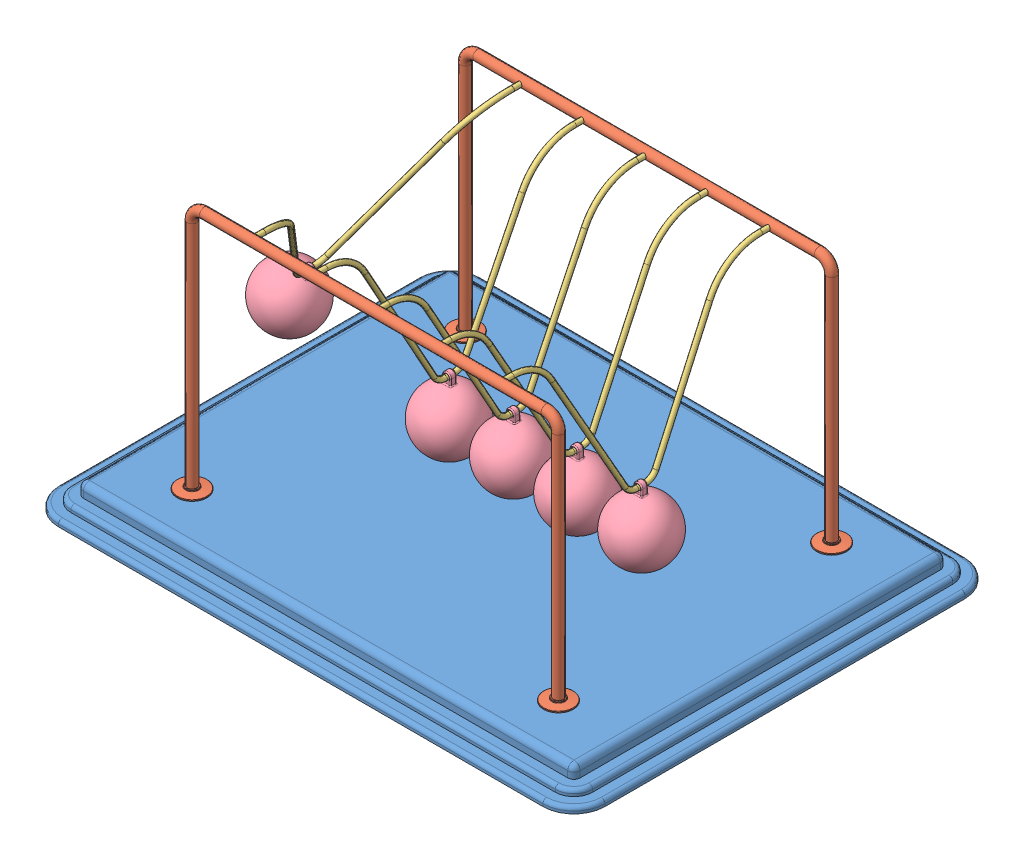
SolidWorks assembly Newtons Cradle NewtonsCradle 0247, configuration Default. Lengths in mm.
Overall size (440 222 340).
13 component instances, 4 part files, 34 mates.
Components (placement in the parent):
- Base 200,162074554295-1: Base 200,162074554295 [Default] at (-16.2968 -4.1587 11.425) size (440 20 340)
- frame NewtonsCradle 0247-1: frame NewtonsCradle 0247 [Default] at (-16.2968 144.4547 -98.575) size (319 202 24)
- frame NewtonsCradle 0247-2: frame NewtonsCradle 0247 [Default] at (-16.2968 144.4547 121.425) x (-1 0 0) z (0 0 -1) size (319 202 24)
- Hanging thing NewtonsCradle 0247-1: Hanging thing NewtonsCradle 0247 [Default] at (-157.6326 134.1825 11.425) x (0 0 1) z (-0.859985 0.510319 0) size (220 129 4)
- Hanging thing NewtonsCradle 0247-2: Hanging thing NewtonsCradle 0247 [Default] at (-66.576 122.8418 11.425) x (0 0 1) z (-0.999994 0.003446 0) size (220 129 4)
- Hanging thing NewtonsCradle 0247-3: Hanging thing NewtonsCradle 0247 [Default] at (-15.6923 122.8436 11.425) x (0 0 1) z (-0.999972 -0.007464 0) size (220 129 4)
- Hanging thing NewtonsCradle 0247-4: Hanging thing NewtonsCradle 0247 [Default] at (35.2213 122.8555 11.425) x (0 0 1) z (-0.999824 -0.018742 0) size (220 129 4)
- Hanging thing NewtonsCradle 0247-5: Hanging thing NewtonsCradle 0247 [Default] at (86.0287 122.8747 11.425) x (0 0 1) z (-0.999588 -0.028711 0) size (220 129 4)
- Sphere NewtonsCradle 0247-1: Sphere NewtonsCradle 0247 [Default] at (-195.3962 70.5436 11.425) x (0.859985 -0.510319 0) z (0 0 1) size (50 58.5 50)
- Sphere NewtonsCradle 0247-2: Sphere NewtonsCradle 0247 [Default] at (88.1533 48.9052 11.425) x (0.999588 0.028711 0) z (0 0 1) size (50 58.5 50)
- Sphere NewtonsCradle 0247-3: Sphere NewtonsCradle 0247 [Default] at (-15.14 48.8456 11.425) x (0.999972 0.007464 0) z (0 0 1) size (50 58.5 50)
- Sphere NewtonsCradle 0247-4: Sphere NewtonsCradle 0247 [Default] at (36.6081 48.8685 11.425) x (0.999824 0.018742 0) z (0 0 1) size (50 58.5 50)
- Sphere NewtonsCradle 0247-5: Sphere NewtonsCradle 0247 [Default] at (-66.831 48.8422 11.425) x (0.999994 -0.003446 0) z (0 0 1) size (50 58.5 50)
Mates (geometry in assembly coordinates):
- Coincident1: coincident anti-aligned: plane of Base-1 through (-211.2968 5.8413 156.425) normal (0 1 0); plane of frame-2 through (-175.7968 5.8413 121.425) normal (0 -1 0)
- Coincident2: coincident anti-aligned: plane of Base-1 through (-211.2968 5.8413 156.425) normal (0 1 0); plane of frame-1 through (143.2032 5.8413 -98.575) normal (0 -1 0)
- Concentric1: concentric anti-aligned: cylinder of frame-1 through (-116.2968 203.8413 -94.575) axis (0 0 -1) radius 2; cylinder of frame-2 through (-116.2968 203.8413 117.425) axis (0 0 1) radius 2
- Concentric2: concentric anti-aligned: cylinder of frame-1 through (83.7032 203.8413 -94.575) axis (0 0 -1) radius 2; cylinder of frame-2 through (83.7032 203.8413 117.425) axis (0 0 1) radius 2
- Distance1: distance = 60 mm: plane of frame-1 through (-16.2968 144.4547 -98.575) normal (0 0 1); line of Base-1 through (-211.2968 -12.1587 -158.575) axis (1 0 0)
- Distance2: distance = 60 mm: line of Base-1 through (178.7032 -12.1587 181.425) axis (-1 0 0); plane of frame-2 through (-16.2968 144.4547 121.425) normal (0 0 -1)
- Distance3: distance = 220 mm: plane of frame-2 through (-16.2968 144.4547 121.425) normal (-1 0 0); line of Base-1 through (-236.2968 -12.1587 156.425) axis (0 0 -1)
- Concentric3: concentric anti-aligned: cylinder of frame-1 through (-116.2968 203.8413 -94.575) axis (0 0 -1) radius 2; cylinder of Hanging thing-1 through (-116.2968 203.8413 111.425) axis (0 0 1) radius 2
- Concentric4: concentric anti-aligned: cylinder of frame-1 through (-116.2968 203.8413 -94.575) axis (0 0 -1) radius 2; cylinder of Hanging thing-1 through (-116.2968 203.8413 -98.575) axis (0 0 1) radius 2
- Concentric5: concentric aligned: cylinder of frame-2 through (-66.2968 203.8413 117.425) axis (0 0 1) radius 2; cylinder of Hanging thing-2 through (-66.2968 203.8413 111.425) axis (0 0 1) radius 2
- Concentric6: concentric aligned: cylinder of frame-2 through (-16.2968 203.8413 117.425) axis (0 0 1) radius 2; cylinder of Hanging thing-3 through (-16.2968 203.8413 111.425) axis (0 0 1) radius 2
- Concentric7: concentric aligned: cylinder of frame-2 through (33.7032 203.8413 117.425) axis (0 0 1) radius 2; cylinder of Hanging thing-4 through (33.7032 203.8413 111.425) axis (0 0 1) radius 2
- Concentric8: concentric aligned: cylinder of frame-2 through (83.7032 203.8413 117.425) axis (0 0 1) radius 2; cylinder of Hanging thing-5 through (83.7032 203.8413 111.425) axis (0 0 1) radius 2
- Coincident5: coincident anti-aligned: plane of frame-2 through (83.7032 203.8413 121.425) normal (0 0 -1); plane of Hanging thing-5 through (83.7032 203.8413 121.425) normal (0 0 1)
- Coincident6: coincident anti-aligned: plane of frame-2 through (33.7032 203.8413 121.425) normal (0 0 -1); plane of Hanging thing-4 through (33.7032 203.8413 121.425) normal (0 0 1)
- Coincident7: coincident anti-aligned: plane of frame-2 through (-16.2968 203.8413 121.425) normal (0 0 -1); plane of Hanging thing-3 through (-16.2968 203.8413 121.425) normal (0 0 1)
- Coincident8: coincident anti-aligned: plane of frame-2 through (-66.2968 203.8413 121.425) normal (0 0 -1); plane of Hanging thing-2 through (-66.2968 203.8413 121.425) normal (0 0 1)
- Coincident9: coincident anti-aligned: plane of frame-2 through (-116.2968 203.8413 121.425) normal (0 0 -1); plane of Hanging thing-1 through (-116.2968 203.8413 121.425) normal (0 0 1)
- Concentric9: concentric anti-aligned: cylinder of Hanging thing-1 through (-117.0163 78.8434 7.925) axis (0 0 1) radius 2; cylinder of Sphere-1 through (-117.0163 78.8434 13.925) axis (0 0 -1) radius 2
- Concentric13: concentric anti-aligned: cylinder of Hanging thing-2 through (-66.7276 78.842 7.925) axis (0 0 1) radius 2; cylinder of Sphere-5 through (-66.7276 78.842 13.925) axis (0 0 -1) radius 2
- Concentric15: concentric anti-aligned: cylinder of Hanging thing-3 through (-15.3639 78.8448 7.925) axis (0 0 1) radius 2; cylinder of Sphere-3 through (-15.3639 78.8448 13.925) axis (0 0 -1) radius 2
- Concentric16: concentric anti-aligned: cylinder of Hanging thing-5 through (87.292 78.8928 7.925) axis (0 0 1) radius 2; cylinder of Sphere-2 through (87.292 78.8928 13.925) axis (0 0 -1) radius 2
- Concentric17: concentric anti-aligned: cylinder of Hanging thing-4 through (36.0459 78.8632 7.925) axis (0 0 1) radius 2; cylinder of Sphere-4 through (36.0459 78.8632 13.925) axis (0 0 -1) radius 2
- Parallel1: parallel anti-aligned: plane of Hanging thing-1; plane of Sphere-1
- Coincident22: coincident anti-aligned: plane of Hanging thing-1; plane of Sphere-1
- Coincident12: coincident aligned: plane of Hanging thing-2 through (-66.576 122.8418 11.425) normal (0 0 1); plane of Sphere-5 through (-66.831 48.8422 11.425) normal (0 0 1)
- Coincident10: coincident aligned: plane of Hanging thing-1 through (-116.763 122.8426 11.425) normal (0 0 1); plane of Sphere-1 through (-118.5806 48.8842 11.425) normal (0 0 1)
- Coincident13: coincident anti-aligned: plane of Hanging thing-2 through (-66.576 122.8418 11.425) normal (-0.999994 0.003446 0); plane of Sphere-5 through (-66.831 48.8422 11.425) normal (0.999994 -0.003446 0)
- Coincident14: coincident anti-aligned: plane of Hanging thing-3 through (-15.6923 122.8436 11.425) normal (-0.999972 -0.007464 0); plane of Sphere-3 through (-15.14 48.8456 11.425) normal (0.999972 0.007464 0)
- Coincident15: coincident aligned: plane of Hanging thing-3 through (-15.6923 122.8436 11.425) normal (0 0 1); plane of Sphere-3 through (-15.14 48.8456 11.425) normal (0 0 1)
- Coincident18: coincident aligned: plane of Hanging thing-4 through (35.2213 122.8555 11.425) normal (0 0 1); plane of Sphere-4 through (36.6081 48.8685 11.425) normal (0 0 1)
- Coincident19: coincident anti-aligned: plane of Hanging thing-4 through (35.2213 122.8555 11.425) normal (-0.999824 -0.018742 0); plane of Sphere-4 through (36.6081 48.8685 11.425) normal (0.999824 0.018742 0)
- Coincident20: coincident anti-aligned: plane of Hanging thing-5 through (86.0287 122.8747 11.425) normal (-0.999588 -0.028711 0); plane of Sphere-2 through (88.1533 48.9052 11.425) normal (0.999588 0.028711 0)
- Coincident21: coincident aligned: plane of Hanging thing-5 through (86.0287 122.8747 11.425) normal (0 0 1); plane of Sphere-2 through (88.1533 48.9052 11.425) normal (0 0 1)
